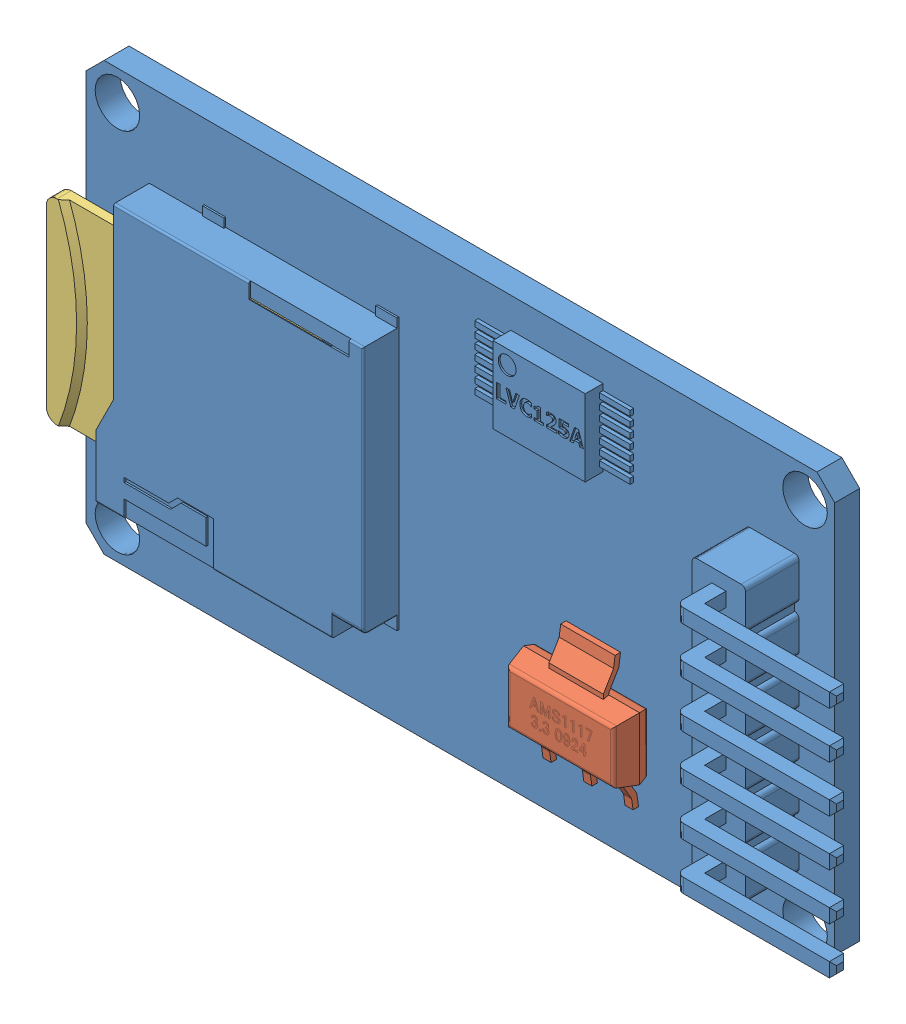
SolidWorks assembly MicroSD Reader Assembly, configuration Default. Lengths in mm.
Overall size (46.9 24 6.7).
4 component instances, 3 part files, 0 mates.
Components (placement in the parent):
- MicroSD Reader Assembly.stp-1: MicroSD Reader Assembly.stp [Default] at origin size (46.9 24 6.7)
  - sdreader.stp-1: sdreader.stp [Default] at (-11.2744 2.632 -3.2) size (46.9 24 6.7)
  - AMS1117.stp-1: AMS1117.stp [Default] at (-0.4339 -2.128 -1.13) x (1 0 0) z (0 -1 0) size (6.51 1.86 7)
  - card sd.stp-1: card sd.stp [Default] at (-21.187 5.4466 -0.36) x (0 -1 0) z (0 0 1) size (11 15 0.82)
